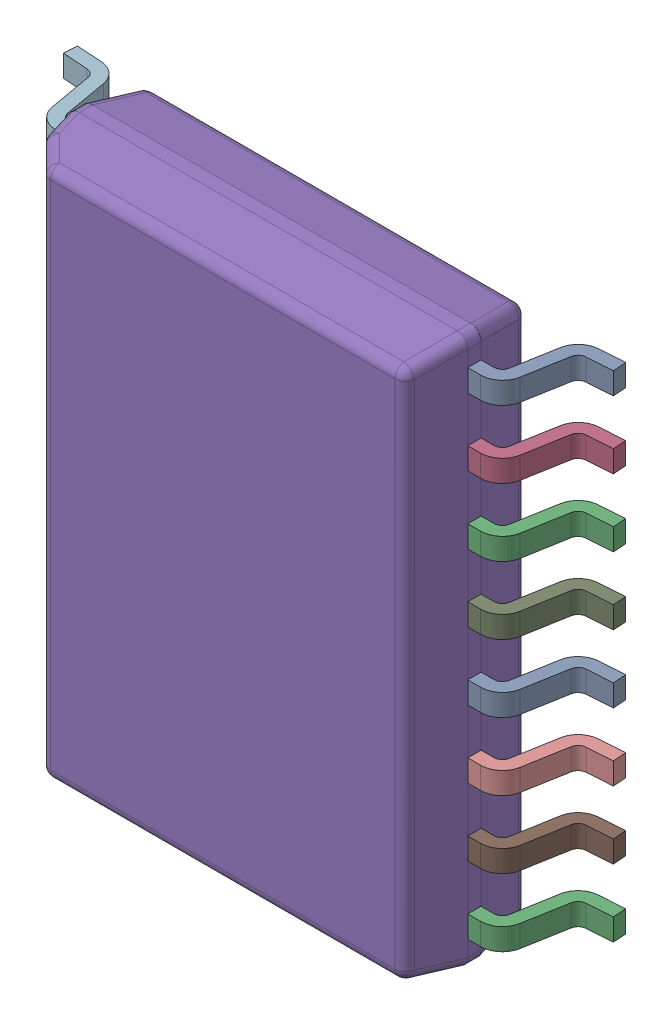
SolidWorks assembly IC4, configuration По умолчанию. Lengths in mm.
Overall size (10.33 10.3 2.59).
18 component instances, 2 part files, 0 mates.
Components (placement in the parent):
- DW0016B_ASM-1: DW0016B_ASM [По умолчанию] at origin size (10.33 10.3 2.59)
  - DW0016B_ASM-Part-1-1: DW0016B_ASM-Part-1 [По умолчанию] at (4.315 -0.635 0.25) x (0 1 0) z (1 0 0) size (0.41 1.57 1.42)
  - DW0016B_ASM-Part-1-2: DW0016B_ASM-Part-1 [По умолчанию] at (-4.315 -1.905 0.25) x (0 -1 0) z (-1 0 0) size (0.41 1.57 1.42)
  - DW0016B_ASM-Part-1-3: DW0016B_ASM-Part-1 [По умолчанию] at (4.315 -4.445 0.25) x (0 1 0) z (1 0 0) size (0.41 1.57 1.42)
  - DW0016B_ASM-Part-1-4: DW0016B_ASM-Part-1 [По умолчанию] at (4.315 3.175 0.25) x (0 1 0) z (1 0 0) size (0.41 1.57 1.42)
  - DW0016B_ASM-Part-1-5: DW0016B_ASM-Part-1 [По умолчанию] at (-4.315 0.635 0.25) x (0 -1 0) z (-1 0 0) size (0.41 1.57 1.42)
  - DW0016B_ASM-Part-1-6: DW0016B_ASM-Part-1 [По умолчанию] at (-4.315 -3.175 0.25) x (0 -1 0) z (-1 0 0) size (0.41 1.57 1.42)
  - DW0016B_ASM-Part-1-7: DW0016B_ASM-Part-1 [По умолчанию] at (-4.315 -4.445 0.25) x (0 -1 0) z (-1 0 0) size (0.41 1.57 1.42)
  - DW0016B_ASM-Part-1-8: DW0016B_ASM-Part-1 [По умолчанию] at (-4.315 3.175 0.25) x (0 -1 0) z (-1 0 0) size (0.41 1.57 1.42)
  - DW0016B_ASM-Part-1-9: DW0016B_ASM-Part-1 [По умолчанию] at (4.315 0.635 0.25) x (0 1 0) z (1 0 0) size (0.41 1.57 1.42)
  - DW0016B_ASM-Part-1-10: DW0016B_ASM-Part-1 [По умолчанию] at (4.315 -1.905 0.25) x (0 1 0) z (1 0 0) size (0.41 1.57 1.42)
  - DW0016B_ASM-Part-1-11: DW0016B_ASM-Part-1 [По умолчанию] at (4.315 -3.175 0.25) x (0 1 0) z (1 0 0) size (0.41 1.57 1.42)
  - DW0016B_ASM-Part-1-12: DW0016B_ASM-Part-1 [По умолчанию] at (-4.315 4.445 0.25) x (0 -1 0) z (-1 0 0) size (0.41 1.57 1.42)
  - DW0016B_ASM-Part-1-13: DW0016B_ASM-Part-1 [По умолчанию] at (4.315 4.445 0.25) x (0 1 0) z (1 0 0) size (0.41 1.57 1.42)
  - DW0016B_ASM-Part-1-14: DW0016B_ASM-Part-1 [По умолчанию] at (-4.315 1.905 0.25) x (0 -1 0) z (-1 0 0) size (0.41 1.57 1.42)
  - DW0016B_ASM-Part-1-15: DW0016B_ASM-Part-1 [По умолчанию] at (4.315 1.905 0.25) x (0 1 0) z (1 0 0) size (0.41 1.57 1.42)
  - DW0016B_ASM-Part-1-16: DW0016B_ASM-Part-1 [По умолчанию] at (-4.315 -0.635 0.25) x (0 -1 0) z (-1 0 0) size (0.41 1.57 1.42)
  - DW0016B_ASM-Part-2-1: DW0016B_ASM-Part-2 [По умолчанию] at (0 0 1.568) x (0 1 0) z (1 0 0) size (10.3 2.29 7.5)
